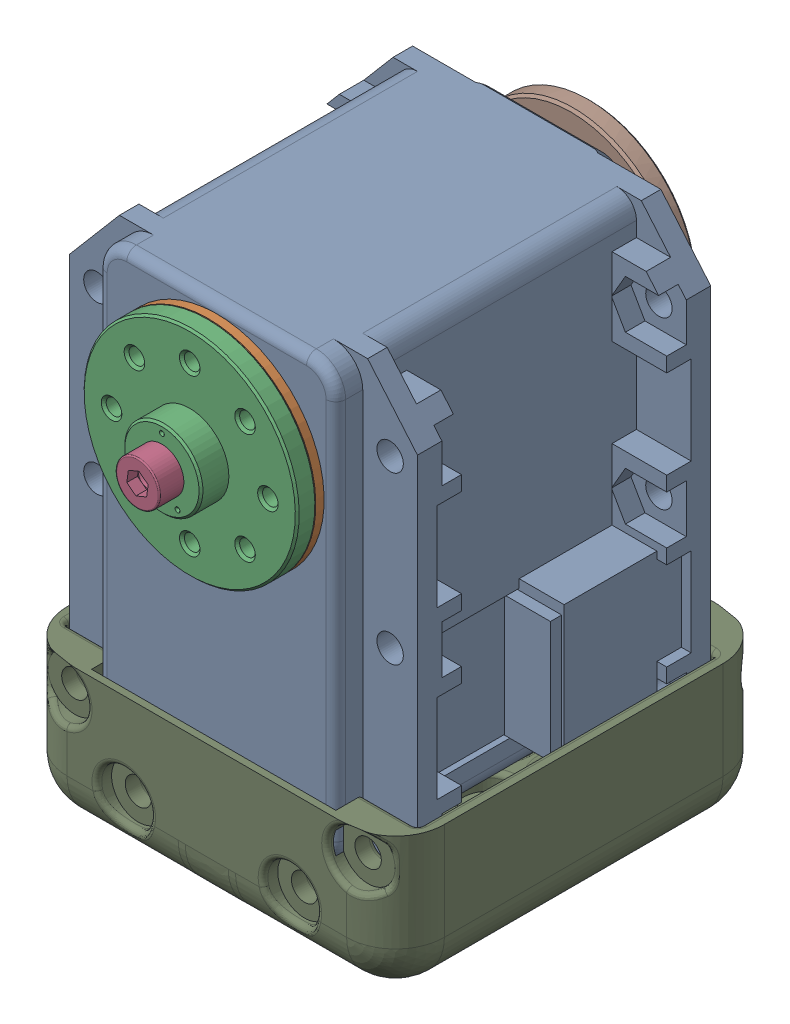
SolidWorks assembly shoulder_x-1, configuration Default. Lengths in mm.
Overall size (38.6 59.63 48.85).
10 component instances, 8 part files, 0 mates.
Components (placement in the parent):
- MX-28(U)-9-1: MX-28(U)-9 [Default] at (11.7145 14.4166 -1.625) size (35.6 54.13 48.5)
  - dynamixel_x28series(U)-1: dynamixel_x28series(U) [Default] at origin size (35.6 50.71 41.85)
  - trust_washer(U)-1: trust_washer(U) [Default] at (0 0 18.6) x (-0.666375 -0.745617 0) z (0.745617 -0.666375 0) size (22 0.85 22)
  - HN07-N101(U)-1: HN07-N101(U) [Default] at (0 0 18.5) x (1 0 0) z (0 -1 0) size (22 5.85 22)
  - WB_M2.5x8-1: WB_M2.5x8 [Default] at (0 0 25.85) x (0 0 -1) z (-0.991137 0.132843 0) size (10.5 4.5 4.5)
  - WB_M2.5x8-2: WB_M2.5x8 [Default] at (0 0 -22.65) x (0 0 1) z (-0.936501 0.350665 0) size (10.5 4.5 4.5)
  - RX28-CAP-1: RX28-CAP [Default] at (0 0 -20.35) x (-0.995735 -0.092256 0) z (0 0 -1) size (7.2 7.2 1.8)
  - MF106ZZ-1: MF106ZZ [Default] at (0 0 -20.35) x (0.888333 -0.4592 0) z (-0.4592 -0.888333 0) size (11.2 3 11.2)
  - HN07-i101-1: HN07-i101 [Default] at (0 0 -20.5) x (1 0 0) z (0 1 0) size (22 3.05 22)
- arm_connector-1: arm_connector [Default] at (11.7145 -28.1834 -11.625) size (38.6 17.77 41.99)
